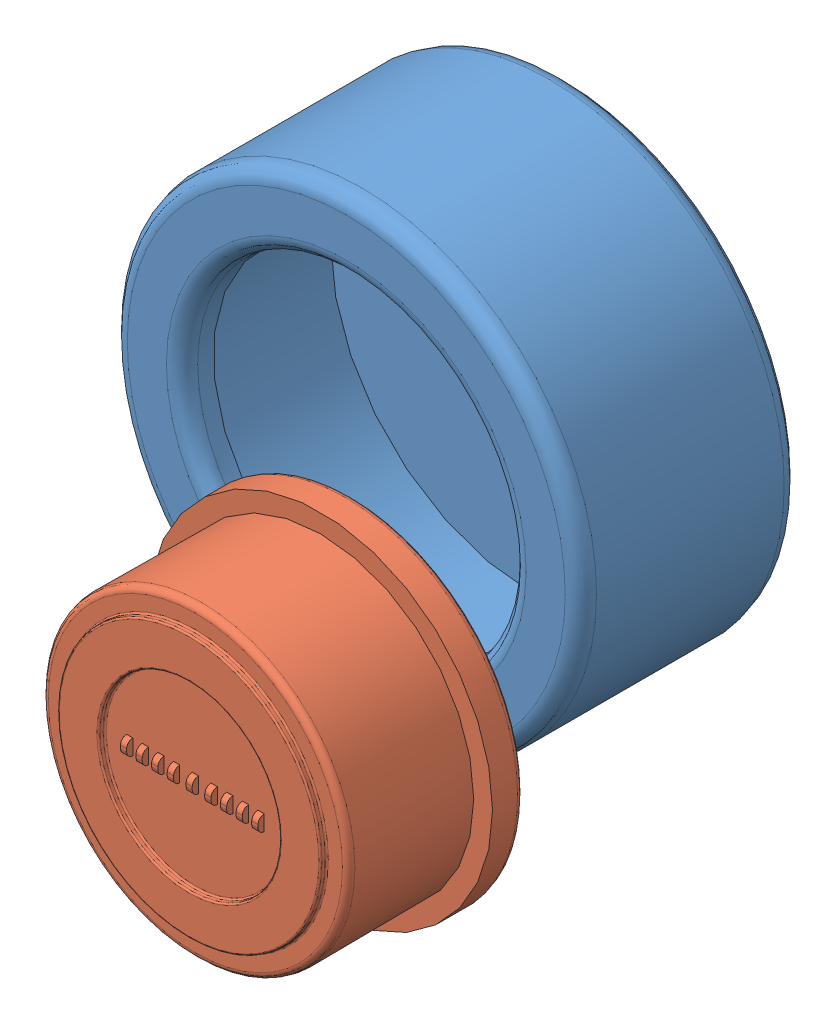
SolidWorks assembly 装配体2, configuration Default. Lengths in mm.
Overall size (17.69 15 16.71).
2 component instances, 2 part files, 0 mates.
Components (placement in the parent):
- 充电座V1.0-磁吸接头固定-1: 充电座V1.0-磁吸接头固定 [Default] at (4.1467 8.5462 8.2922) size (15 15 7)
- 充电座V1.0-磁吸接头-2: 充电座V1.0-磁吸接头 [Default] at (8.8336 6.9189 24.8034) size (11 11 5.2)
